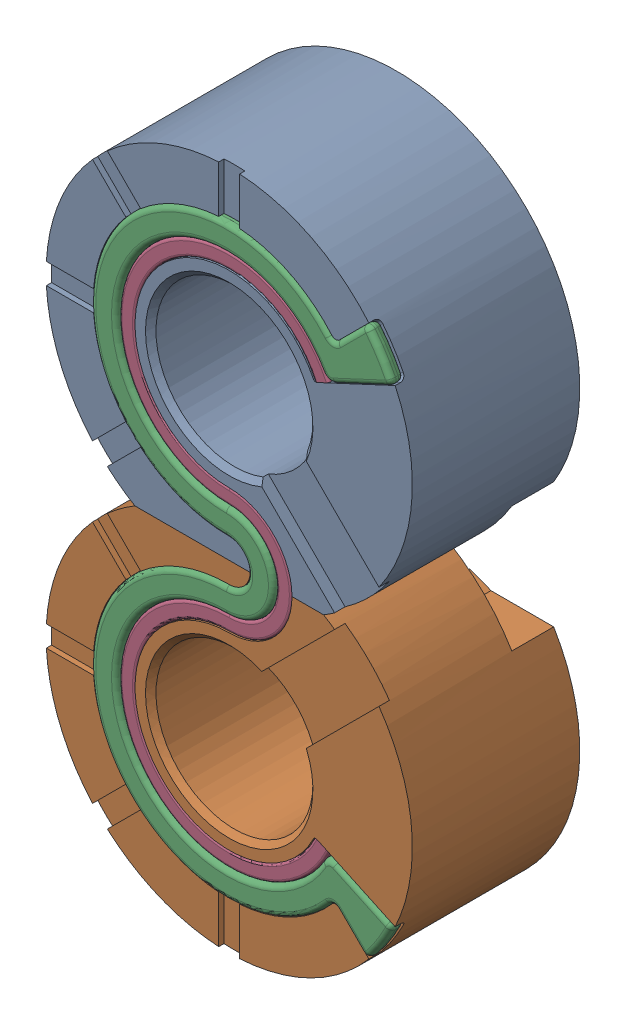
SolidWorks assembly 1.1 Spacer unit sub assembly, configuration Default. Lengths in mm.
Overall size (35 65 16.25).
4 component instances, 4 part files, 9 mates.
Components (placement in the parent):
- 2. Spacer 1-1: 2. Spacer 1 [Default] at origin size (35 32.5 16)
- 3. Spacer 2-1: 3. Spacer 2 [Default] at origin size (35 32.5 16)
- 4. Sealing gasket-1: 4. Sealing gasket [Default] at (0 -2.8979 7) size (28.69 56 1.25)
- 5. Spacer 3-1: 5. Spacer 3 [Default] at (0 0 7) size (20.02 51 1)
Mates (geometry in assembly coordinates):
- Coincident1: coincident anti-aligned: plane of 2. Spacer 1-1 through (-9.0139 0 8) normal (0 -1 0); plane of 3. Spacer 2-1 through (-9.0139 0 8) normal (0 1 0)
- Coincident2: coincident aligned: line of 2. Spacer 1-1 through (9.0139 0 8) axis (0 0 -1); line of 3. Spacer 2-1 through (9.0139 0 8) axis (0 0 -1)
- Coincident3: coincident aligned: plane of 2. Spacer 1-1 through (0 15 8) normal (0 0 1); plane of 3. Spacer 2-1 through (0 -15 8) normal (0 0 1)
- Concentric1: concentric aligned: cylinder of 2. Spacer 1-1 through (0 15 8) axis (0 0 -1) radius 7.5; cylinder of 4. Sealing gasket-1 through (0 15 8.25) axis (0 0 -1) radius 10.5
- Concentric2: concentric aligned: cylinder of 3. Spacer 2-1 through (0 -15 8) axis (0 0 -1) radius 7.5; cylinder of 4. Sealing gasket-1 through (0 -15 8.25) axis (0 0 -1) radius 10.5
- Coincident4: coincident anti-aligned: plane of 3. Spacer 2-1 through (0 -15 7) normal (0 0 1); plane of 4. Sealing gasket-1 through (0 15 7) normal (0 0 -1)
- Concentric3: concentric: cylinder of 2. Spacer 1-1 through (0 15 8) axis (0 0 -1) radius 7.5; cylinder of 5. Spacer 3-1 through (0 15 13.0875) axis (0 0 -1) radius 9
- Concentric4: concentric: cylinder of 3. Spacer 2-1 through (0 -15 8) axis (0 0 -1) radius 7.5; cylinder of 5. Spacer 3-1 through (0 -15 13.0875) axis (0 0 -1) radius 9
- Coincident6: coincident anti-aligned: plane of 3. Spacer 2-1 through (0 -15 7) normal (0 0 1); plane of 5. Spacer 3-1 through (0 15 7) normal (0 0 -1)
